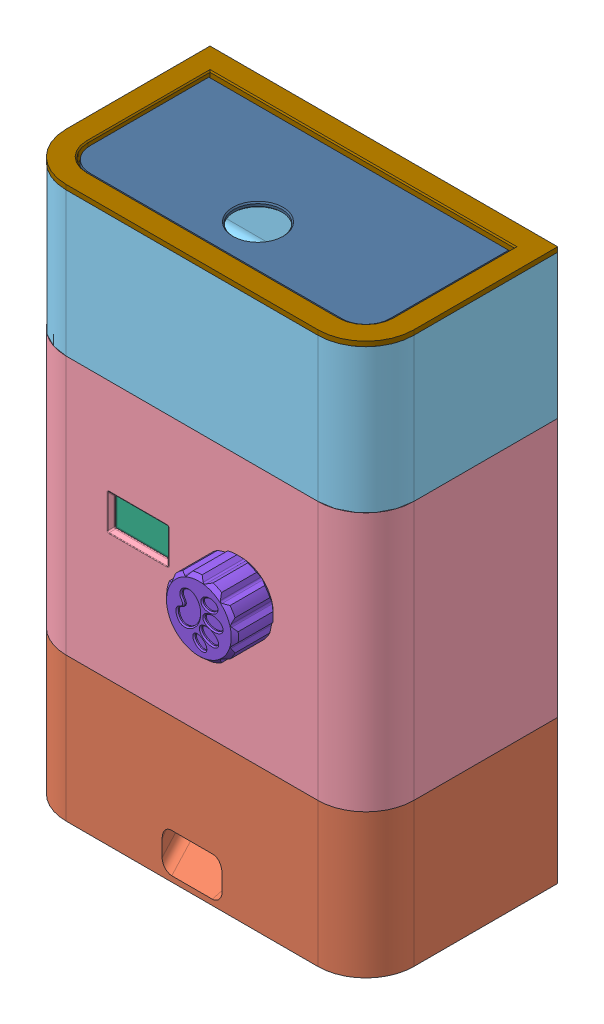
SolidWorks assembly L.013.00.00.00 Cat feeder, configuration По умолчанию. Lengths in mm.
Overall size (145 230 99.65).
10 component instances, 10 part files, 28 mates.
Components (placement in the parent):
- NEMA 17HS13-0404S1-1: NEMA 17HS13-0404S1 [По умолчанию] x (1 0 0) z (0 0 -1) size (42 42 53.2)
- L.013.00.00.01 BodyBottom-2: L.013.00.00.01 BodyBottom [По умолчанию] at (0 0 -3) x (-1 0 0) z (0 -1 0) size (145 80 102.28)
- L.013.00.00.02 Wheel-1: L.013.00.00.02 Wheel [По умолчанию] at (0 0 -32.5) size (46.16 46.12 27.01)
- L.013.00.00.03 BodyTop-2: L.013.00.00.03 BodyTop [По умолчанию] at (0 19.5 -18) x (-1 0 0) z (0 0 -1) size (145 110 80)
- L.013.00.00.04 Tank-1: L.013.00.00.04 Tank [По умолчанию] at (0 147 -35) x (1 0 0) z (0 0 -1) size (145 66.7 80)
- OLED-128x64-0.96-1: OLED-128x64-0.96 [По умолчанию] at (11.8304 41.994 41.795) size (26.7 27.86 10.85)
- Rotary Encoder - KY-040-1: Rotary Encoder - KY-040 [По умолчанию] at (19.985 41.05 36.5) x (0 -1 0) z (0 0 1) size (19 30.75 32.39)
- L.013.00.00.05 Knob-1: L.013.00.00.05 Knob [По умолчанию] at (22.5 39.5 47.15) x (-0.283342 -0.959019 0) z (-0.959019 0.283342 0) size (30 17.5 29.82)
- L.013.00.00.06 CapFrame-1: L.013.00.00.06 CapFrame [По умолчанию] at (0 147 5) size (145 8.7 80)
- L.013.00.00.07 Cap-1: L.013.00.00.07 Cap [По умолчанию] at (0 142 5) size (125 6 60)
Mates (geometry in assembly coordinates):
- Концентричный2: concentric: cylinder of NEMA 17HS13-0404S1-1 through (0 0 -20) axis (0 0 1) radius 2.5; cylinder of L.013.00.00.02 Wheel-1 through (0 0 22.7843) axis (0 0 -1) radius 2.5
- Совпадение1: coincident: plane of NEMA 17HS13-0404S1-1 through (0 0 0) normal (0 0 -1); plane of assembly through (0 0 0) normal (0 0 1)
- Совпадение2: coincident: plane of NEMA 17HS13-0404S1-1 through (0 0 0) normal (0 -1 0); plane of assembly through (0 0 0) normal (0 1 0)
- Совпадение3: coincident: plane of NEMA 17HS13-0404S1-1 through (0 0 0) normal (1 0 0); plane of assembly through (0 0 0) normal (1 0 0)
- Совпадение5: coincident: plane of NEMA 17HS13-0404S1-1 through (0 0 0) normal (0 0 -1); plane of L.013.00.00.01 BodyBottom-2 through (0 0 0) normal (0 0 1)
- Концентричный3: concentric: cylinder of NEMA 17HS13-0404S1-1 through (0 0 -20) axis (0 0 1) radius 2.5; cylinder of L.013.00.00.01 BodyBottom-2 through (0 0 -3) axis (0 0 -1) radius 3.75
- Параллельность4: parallel: plane of NEMA 17HS13-0404S1-1 through (-21 21 33.2) normal (0 1 0); plane of L.013.00.00.01 BodyBottom-2 through (24.5 21 -33) normal (0 1 0)
- Расстояние2: distance = 0.5 mm: plane of L.013.00.00.01 BodyBottom-2 through (0 0 -5) normal (0 0 -1); plane of L.013.00.00.02 Wheel-1 through (18.309 13.9205 -5.5) normal (0 0 1)
- Совпадение6: coincident: plane of L.013.00.00.01 BodyBottom-2 through (0 0 -5) normal (0 0 -1); plane of L.013.00.00.03 BodyTop-2 through (22.5 19.5 -5) normal (0 0 -1)
- Совпадение7: coincident: plane of L.013.00.00.01 BodyBottom-2 through (-22.5 16.6658 67) normal (1 0 0); plane of L.013.00.00.03 BodyTop-2 through (-22.5 19.5 -33) normal (1 0 0)
- Совпадение11: coincident: plane of L.013.00.00.01 BodyBottom-2 through (79.1224 -21 45) normal (0 0.707107 -0.707107); plane of L.013.00.00.03 BodyTop-2 through (72.5 -21 45) normal (0 -0.707107 0.707107)
- Совпадение13: coincident: plane of L.013.00.00.03 BodyTop-2 through (72.5 -22.5 -35) normal (0 0 -1); plane of L.013.00.00.04 Tank-1 through (-72.5 87 -35) normal (0 0 -1)
- Совпадение15: coincident: plane of L.013.00.00.03 BodyTop-2 through (72.5 123 -33) normal (1 0 0); plane of L.013.00.00.04 Tank-1 through (72.5 87 -35) normal (1 0 0)
- Совпадение18: coincident: plane of L.013.00.00.03 BodyTop-2 through (52.5 87 25) normal (0 1 0); plane of L.013.00.00.04 Tank-1 through (-52.5 87 25) normal (0 -1 0)
- Совпадение22: coincident: plane of L.013.00.00.03 BodyTop-2 through (52.5 -22.5 43) normal (0 0 -1); plane of OLED-128x64-0.96-1 through (-22.5 38.99 43) normal (0 0 1)
- Ширина1: width: plane of OLED-128x64-0.96-1 through (-35.75 47.25 41.55) normal (-1 0 0); plane of OLED-128x64-0.96-1 through (-9.25 27.99 41.55) normal (1 0 0); plane of L.013.00.00.03 BodyTop-2 through (-33.75 33.5 70.5) normal (1 0 0); plane of L.013.00.00.03 BodyTop-2 through (-11.25 33.5 70.5) normal (-1 0 0)
- Концентричный4: concentric: cylinder of L.013.00.00.03 BodyTop-2 through (22.5 39.5 70.5) axis (0 0 -1) radius 4; cylinder of Rotary Encoder - KY-040-1 through (22.5 39.5 50.65) axis (0 0 1) radius 3
- Совпадение23: coincident: plane of L.013.00.00.03 BodyTop-2 through (52.5 -22.5 43) normal (0 0 -1); plane of Rotary Encoder - KY-040-1 through (22.5 39.5 43) normal (0 0 1)
- Ширина2: width: plane of OLED-128x64-0.96-1 through (-9.25 31.75 41.55) normal (0 -1 0); plane of OLED-128x64-0.96-1 through (-9.25 47.25 41.55) normal (0 1 0); plane of L.013.00.00.03 BodyTop-2 through (-11.25 45.5 70.5) normal (0 -1 0); plane of L.013.00.00.03 BodyTop-2 through (-11.25 33.5 70.5) normal (0 1 0)
- Концентричный5: concentric: cylinder of Rotary Encoder - KY-040-1 through (22.5 39.5 50.65) axis (0 0 1) radius 3; cylinder of L.013.00.00.05 Knob-1 through (22.5 39.5 64.65) axis (0 0 1) radius 3.125
- Совпадение24: coincident: plane of Rotary Encoder - KY-040-1 through (22.5 39.5 63.15) normal (0 0 1); plane of L.013.00.00.05 Knob-1 through (23.3854 42.4969 63.15) normal (0 0 -1)
- Совпадение25: coincident: plane of L.013.00.00.04 Tank-1 through (-72.5 87 -35) normal (0 0 -1); plane of L.013.00.00.06 CapFrame-1 through (-72.5 149 -35) normal (0 0 -1)
- Совпадение26: coincident: plane of L.013.00.00.04 Tank-1 through (72.5 87 -35) normal (1 0 0); plane of L.013.00.00.06 CapFrame-1 through (72.5 149 45) normal (1 0 0)
- Совпадение27: coincident: plane of L.013.00.00.04 Tank-1 through (-52.5 147 25) normal (0 1 0); plane of L.013.00.00.06 CapFrame-1 through (0 147 5) normal (0 -1 0)
- Концентричный6: concentric: cylinder of L.013.00.00.06 CapFrame-1 through (-72.5 146 -23) axis (1 0 0) radius 1; cylinder of L.013.00.00.07 Cap-1 through (52.5 146 -23) axis (1 0 0) radius 1
- Ширина3: width: plane of L.013.00.00.06 CapFrame-1 through (63.5 147 25) normal (-1 0 0); plane of L.013.00.00.06 CapFrame-1 through (-63.5 147 -26) normal (1 0 0); plane of L.013.00.00.07 Cap-1 through (62.5 148 35) normal (1 0 0); plane of L.013.00.00.07 Cap-1 through (-62.5 148 35) normal (-1 0 0)
- Граничный угол1: limit planar angle = 1.570796 rad: plane of L.013.00.00.07 Cap-1 through (-62.5 148 -25) normal (0 0 -1); plane of L.013.00.00.06 CapFrame-1 through (0 149 5) normal (0 1 0)
- Параллельность5: parallel: plane of L.013.00.00.03 BodyTop-2 through (72.5 123 -33) normal (1 0 0); plane of Rotary Encoder - KY-040-1 through (28.45 33.55 36.5) normal (1 0 0)
